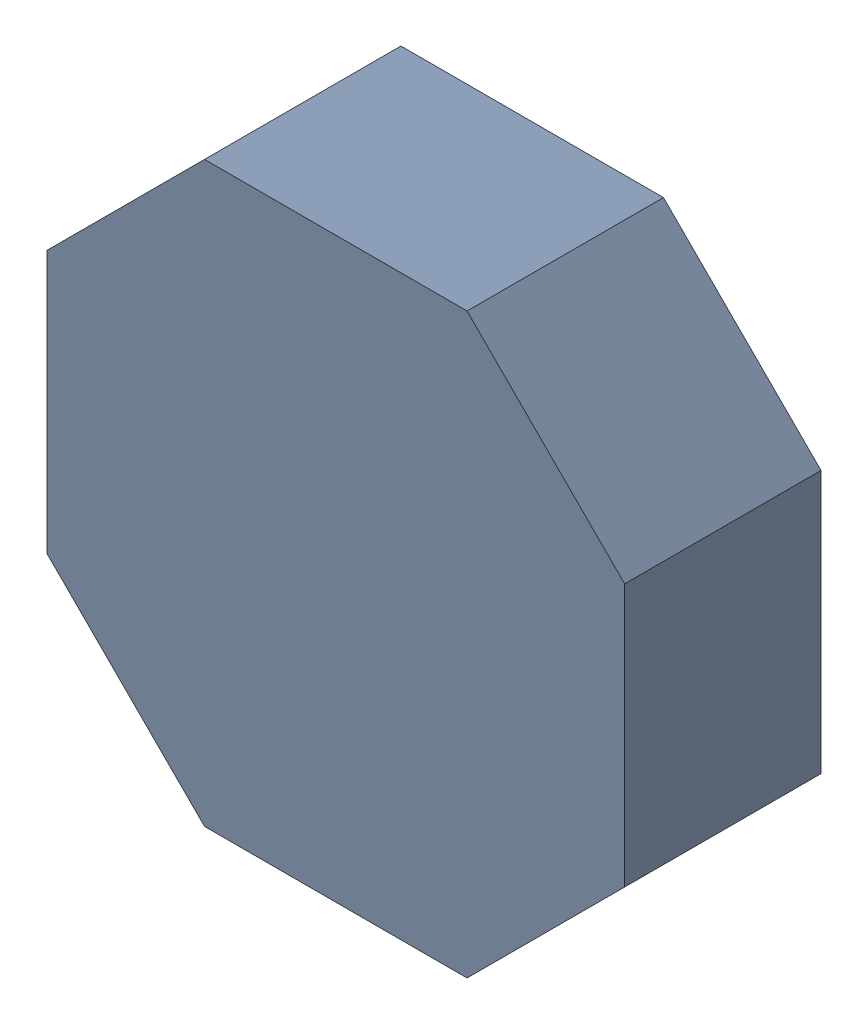
SolidWorks assembly 15uHKanaloa_v2.0.0_Power, configuration Default. Lengths in mm.
Overall size (11.18 11.18 3.8).
2 component instances, 1 part files, 0 mates.
Components (placement in the parent):
- 378151616-1: 378151616 [Default] at (137.0468 106.3224 0) size (11.18 11.18 3.8)
  - Extruded_21-1: Extruded_21 [Default] at origin size (11.18 11.18 3.8)
